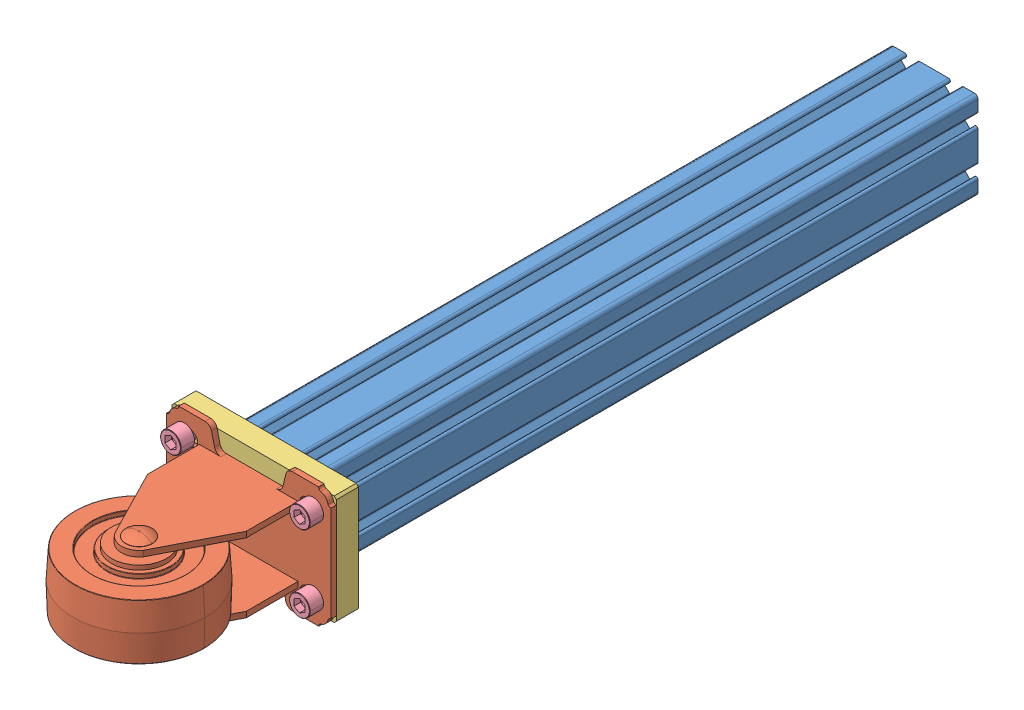
SolidWorks assembly Assem1, configuration Default. Lengths in mm.
Overall size (95.25 69.85 498.48).
7 component instances, 4 part files, 15 mates.
Components (placement in the parent):
- 2020_S_15CL-1: 2020_S_15CL [Default] at (127.6783 230.2754 280.6829) size (50.8 50.8 381)
- 2311-1: 2311 [Default] at (143.3761 231.1522 539.8372) x (1 0 0) z (0 1 0) size (95.25 104.78 69.85)
- 2418-1: 2418 [Default] at (89.8147 170.5028 471.1829) x (1 0 0) z (0 0 1) size (95.25 63.51 12.7)
- WHEELSCREW-1: WHEELSCREW [Default] at (177.7163 239.8004 487.0579) x (0 0 -1) z (1 0 0) size (23.8 11.91 11.91)
- WHEELSCREW-2: WHEELSCREW [Default] at (177.7163 195.3504 487.0579) x (0 0 -1) z (1 0 0) size (23.8 11.91 11.91)
- WHEELSCREW-3: WHEELSCREW [Default] at (103.0403 239.8004 487.0579) x (0 0 -1) z (1 0 0) size (23.8 11.91 11.91)
- WHEELSCREW-4: WHEELSCREW [Default] at (103.0403 195.3504 487.0579) x (0 0 -1) z (1 0 0) size (23.8 11.91 11.91)
Mates (geometry in assembly coordinates):
- Concentric1: concentric aligned: cylinder of 2020_S_15CL-1 through (127.6783 230.2754 471.1829) axis (0 0 1) radius 2.6035; circle of 2418-1
- Concentric2: concentric aligned: circle of 2020_S_15CL-1; circle of 2418-1
- Coincident1: coincident anti-aligned: plane of 2020_S_15CL-1 through (116.0832 200.5193 471.1829) normal (0 0 1); plane of 2418-1 through (89.8147 170.5028 471.1829) normal (0 0 -1)
- Coincident2: coincident aligned: plane of 2311-1 through (188.0033 189.7712 483.8829) normal (1 0 0); plane of 2418-1 through (188.0033 187.0954 471.1829) normal (1 0 0)
- Coincident5: coincident anti-aligned: plane of 2311-1 through (92.9103 188.1964 483.8829) normal (0 0 -1); plane of 2418-1 through (89.8147 170.5028 483.8829) normal (0 0 1)
- Coincident6: coincident aligned: plane of 2311-1 through (188.0033 189.7712 483.8829) normal (1 0 0); plane of 2418-1 through (188.0033 187.0954 471.1829) normal (1 0 0)
- Concentric5: concentric aligned: circle of 2418-1; circle of WHEELSCREW-1
- Coincident11: coincident anti-aligned: plane of 2311-1 through (92.9103 188.1964 487.0579) normal (0 0 1); plane of WHEELSCREW-1 through (177.7163 245.7567 487.0579) normal (0 0 -1)
- Concentric6: concentric aligned: circle of 2418-1; circle of WHEELSCREW-2
- Coincident12: coincident anti-aligned: plane of 2311-1 through (92.9103 188.1964 487.0579) normal (0 0 1); plane of WHEELSCREW-2 through (177.7163 201.3067 487.0579) normal (0 0 -1)
- Concentric7: concentric aligned: circle of 2418-1; circle of WHEELSCREW-3
- Coincident13: coincident anti-aligned: plane of 2311-1 through (92.9103 188.1964 487.0579) normal (0 0 1); plane of WHEELSCREW-3 through (103.0403 245.7567 487.0579) normal (0 0 -1)
- Concentric8: concentric aligned: circle of 2418-1; circle of WHEELSCREW-4
- Coincident14: coincident anti-aligned: plane of 2311-1 through (92.9103 188.1964 487.0579) normal (0 0 1); plane of WHEELSCREW-4 through (103.0403 201.3067 487.0579) normal (0 0 -1)
- Lock1: lock: unknown of 2311-1; unknown of 2418-1
